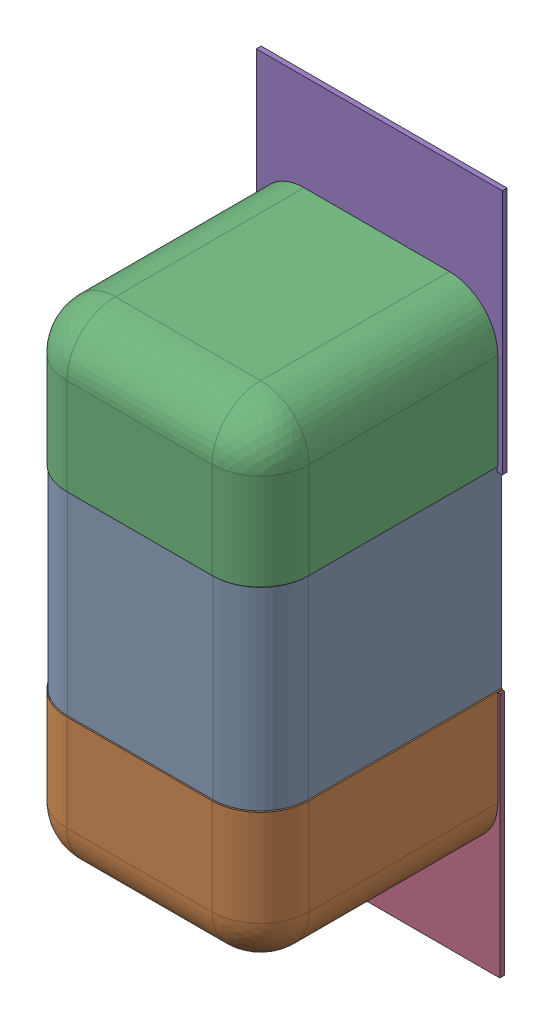
SolidWorks assembly C58, configuration Défaut. Lengths in mm.
Overall size (0.51 1.41 0.5).
8 component instances, 4 part files, 0 mates.
Components (placement in the parent):
- 6501216624-1: 6501216624 [Défaut] at (39.243 -23.3554 0) x (0 1 0) z (1 0 0) size (1 0.5 0.5)
  - Open CASCADE STEP translator 7.5 2.111.1.1-1: Open CASCADE STEP translator 7.5 2.111.1.1 [Défaut] at origin size (0.4 0.5 0.5)
  - Open CASCADE STEP translator 7.5 2.111.1.2-1: Open CASCADE STEP translator 7.5 2.111.1.2 [Défaut] at origin size (0.3 0.5 0.5)
  - Open CASCADE STEP translator 7.5 2.111.1.3-1: Open CASCADE STEP translator 7.5 2.111.1.3 [Défaut] at origin size (0.3 0.5 0.5)
- 6504207776-1: 6504207776 [Défaut] at (39.243 -23.8127 0) size (0.51 0.51 0.01)
  - Extruded-1: Extruded [Défaut] at origin size (0.51 0.51 0.01)
- 6504207776-2: 6504207776 [Défaut] at (39.2482 -22.9104 0) size (0.51 0.51 0.01)
  - Extruded-1: Extruded [Défaut] at origin size (0.51 0.51 0.01)
